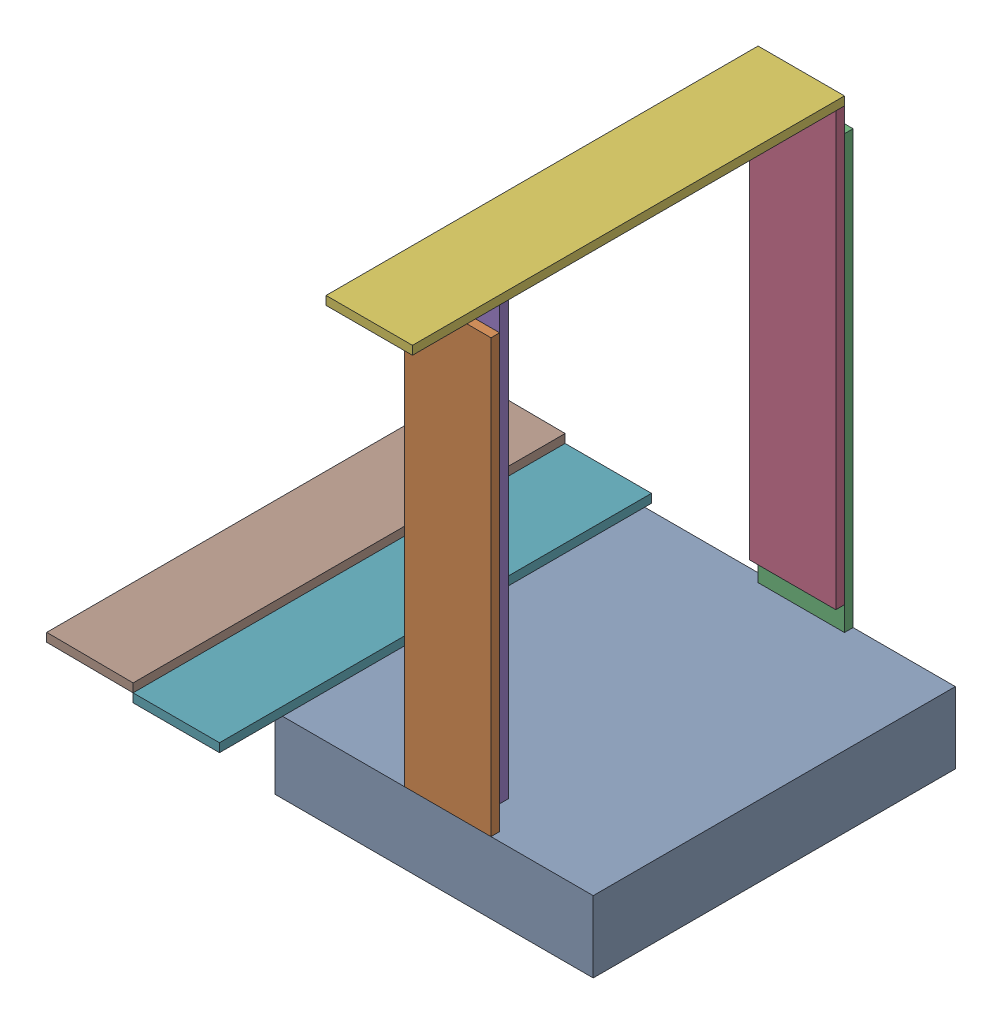
SolidWorks assembly Assem1, configuration Default. Lengths in mm.
Overall size (1063.29 1240.88 1040).
8 component instances, 2 part files, 19 mates.
Components (placement in the parent):
- robot base-1: robot base [Default] at (-409.4342 97.3018 819.4776) size (736.6 165.1 838.2)
- plate1-1: plate1 [Default] at (-109.4342 262.4018 799.4776) size (200 1000 20)
- plate1-2: plate1 [Default] at (-109.4342 262.4018 -18.7224) size (200 1000 20)
- plate1-3: plate1 [Default] at (-109.4342 318.177 1.2776) size (200 1000 20)
- plate1-4: plate1 [Default] at (-109.4342 318.177 779.4776) size (200 1000 20)
- plate1-5: plate1 [Default] at (-109.4342 1338.177 1.2776) x (1 0 0) z (0 -1 0) size (200 1000 20)
- plate1-6: plate1 [Default] at (-536.1259 338.177 21.2776) x (1 0 0) z (0 -1 0) size (200 1000 20)
- plate1-7: plate1 [Default] at (-735.9807 359.5796 21.2776) x (0.999975 -0.007016 0) z (-0.007016 -0.999975 0) size (200 1000 20)
Mates (geometry in assembly coordinates):
- Coincident1: coincident anti-aligned: plane of robot base-1 through (-409.4342 262.4018 819.4776) normal (0 1 0); plane of plate1-1 through (-109.4342 262.4018 819.4776) normal (0 -1 0)
- Coincident2: coincident anti-aligned: plane of robot base-1 through (-409.4342 262.4018 819.4776) normal (0 1 0); plane of plate1-1 through (-109.4342 262.4018 819.4776) normal (0 -1 0)
- Coincident3: coincident aligned: plane of plate1-1 through (-109.4342 262.4018 819.4776) normal (-1 0 0); plane of plate1-2 through (-109.4342 262.4018 1.2776) normal (-1 0 0)
- Coincident4: coincident anti-aligned: plane of robot base-1 through (-409.4342 262.4018 819.4776) normal (0 1 0); plane of plate1-2 through (-109.4342 262.4018 1.2776) normal (0 -1 0)
- Coincident5: coincident anti-aligned: plane of plate1-2 through (-109.4342 262.4018 1.2776) normal (0 0 1); plane of plate1-3 through (-109.4342 318.177 1.2776) normal (0 0 -1)
- Coincident6: coincident aligned: plane of plate1-2 through (-109.4342 262.4018 1.2776) normal (-1 0 0); plane of plate1-3 through (-109.4342 318.177 21.2776) normal (-1 0 0)
- Coincident7: coincident aligned: plane of robot base-1 through (-409.4342 262.4018 -18.7224) normal (0 0 -1); plane of plate1-2 through (-109.4342 262.4018 -18.7224) normal (0 0 -1)
- Coincident8: coincident aligned: plane of robot base-1 through (-409.4342 262.4018 819.4776) normal (0 0 1); plane of plate1-1 through (-109.4342 262.4018 819.4776) normal (0 0 1)
- Coincident9: coincident anti-aligned: plane of plate1-1 through (-109.4342 262.4018 799.4776) normal (0 0 -1); plane of plate1-4 through (-109.4342 318.177 799.4776) normal (0 0 1)
- Coincident10: coincident aligned: plane of plate1-1 through (-109.4342 262.4018 819.4776) normal (-1 0 0); plane of plate1-4 through (-109.4342 318.177 799.4776) normal (-1 0 0)
- Distance1: distance = 300 mm aligned: plane of plate1-1 through (-109.4342 262.4018 819.4776) normal (-1 0 0); plane of robot base-1 through (-409.4342 262.4018 819.4776) normal (-1 0 0)
- Coincident12: coincident aligned: plane of plate1-3 through (-109.4342 1318.177 21.2776) normal (0 1 0); plane of plate1-4 through (-109.4342 1318.177 799.4776) normal (0 1 0)
- Coincident13: coincident anti-aligned: plane of plate1-3 through (-109.4342 1318.177 21.2776) normal (0 1 0); plane of plate1-5 through (-109.4342 1318.177 1.2776) normal (0 -1 0)
- Coincident14: coincident aligned: plane of plate1-3 through (-109.4342 318.177 1.2776) normal (0 0 -1); plane of plate1-5 through (-109.4342 1318.177 1.2776) normal (0 0 -1)
- Coincident15: coincident aligned: plane of plate1-3 through (-109.4342 318.177 21.2776) normal (-1 0 0); plane of plate1-5 through (-109.4342 1318.177 1.2776) normal (-1 0 0)
- Coincident17: coincident anti-aligned: plane of plate1-3 through (-109.4342 318.177 21.2776) normal (0 0 1); plane of plate1-6 through (-536.1259 318.177 21.2776) normal (0 0 -1)
- Coincident19: coincident aligned: plane of plate1-3 through (-109.4342 318.177 21.2776) normal (0 -1 0); plane of plate1-6 through (-536.1259 318.177 21.2776) normal (0 -1 0)
- Coincident22: coincident aligned: plane of plate1-6 through (-536.1259 318.177 1021.2776) normal (0 0 1); plane of plate1-7 through (-736.121 339.5801 1021.2776) normal (0 0 1)
- Coincident23: coincident: point of plate1-6; point of plate1-7
